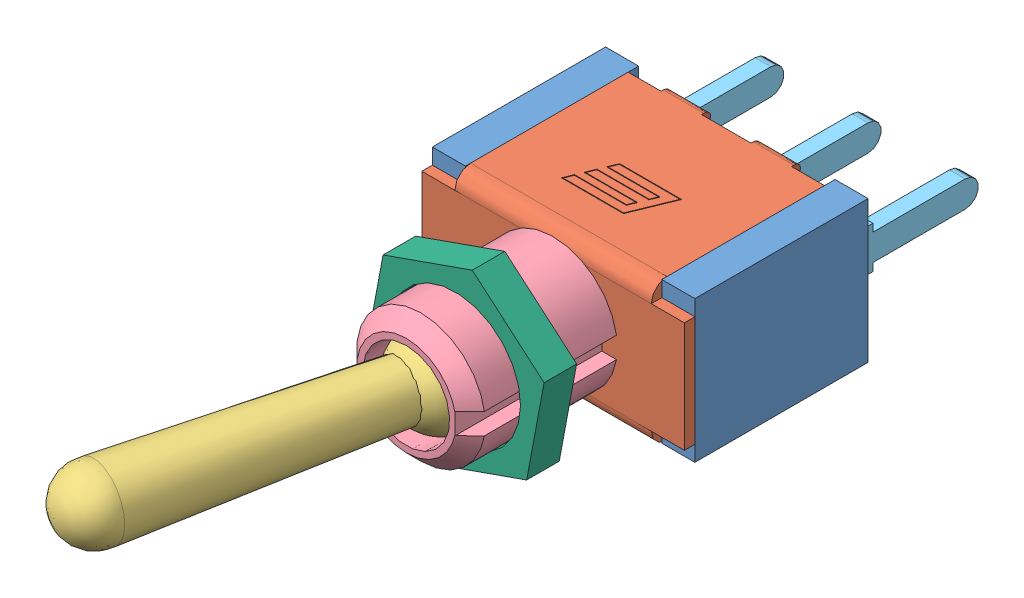
SolidWorks assembly 100SP3T2B3M2RE - TOGGLE, MICRO, 3 POS, .250 THD BUSHING, SHORT BAT, configuration T3. Lengths in mm.
Overall size (12.7 12.2 36.71).
6 component instances, 6 part files, 2 mates.
Components (placement in the parent):
- 100 SP Housing-1: 100 SP Housing [Default] at origin size (12.7 6.86 8.38)
- 100 SP Top Bracket-1: 100 SP Top Bracket [Default] at (0 0 4.445) x (1 0 0) z (0 1 0) size (12.7 8.89 6.86)
- 100 T2-1: 100 T2 [T3] at (0 0 14.32) x (0 -1 0) z (-0.21644 0 0.976296)
- 100 B3 Bushing-1: 100 B3 Bushing [Default] x (-1 0 0) z (0 0 1) size (6.18 6.22 7.1)
- 100 SP M2 Terminal-1: 100 SP M2 Terminal [Default] x (-1 0 0) z (0 0 -1) size (12.56 4.43 6.6)
- Nut^100SP3T2B3M2RE - TOGGLE, MICRO, 3 POS, .250 THD BUSHING, SHORT BAT-1: Nut^100SP3T2B3M2RE - TOGGLE, MICRO, 3 POS, .250 THD BUSHING, SHORT BAT [Default] at (0 0 12.065) x (0.725286 -0.688448 0) z (0 0 1) size (9.14 8.15 1.57) (virtual)
Mates (geometry in assembly coordinates):
- Concentric1: concentric aligned: cylinder of 100 B3 Bushing-1 through (0 0 8.89) axis (0 0 1) radius 3.11; cylinder of Nut^100SP3T2B3M2RE - TOGGLE, MICRO, 3 POS, .250 THD BUSHING, SHORT BAT-1 through (0 0 12.065) axis (0 0 1) radius 3.175
- Distance1: distance = 3.175 mm anti-aligned: plane of Nut^100SP3T2B3M2RE - TOGGLE, MICRO, 3 POS, .250 THD BUSHING, SHORT BAT-1 through (0 0 12.065) normal (0 0 -1); plane of 100 SP Top Bracket-1 through (0 2.67 8.89) normal (0 0 1)
